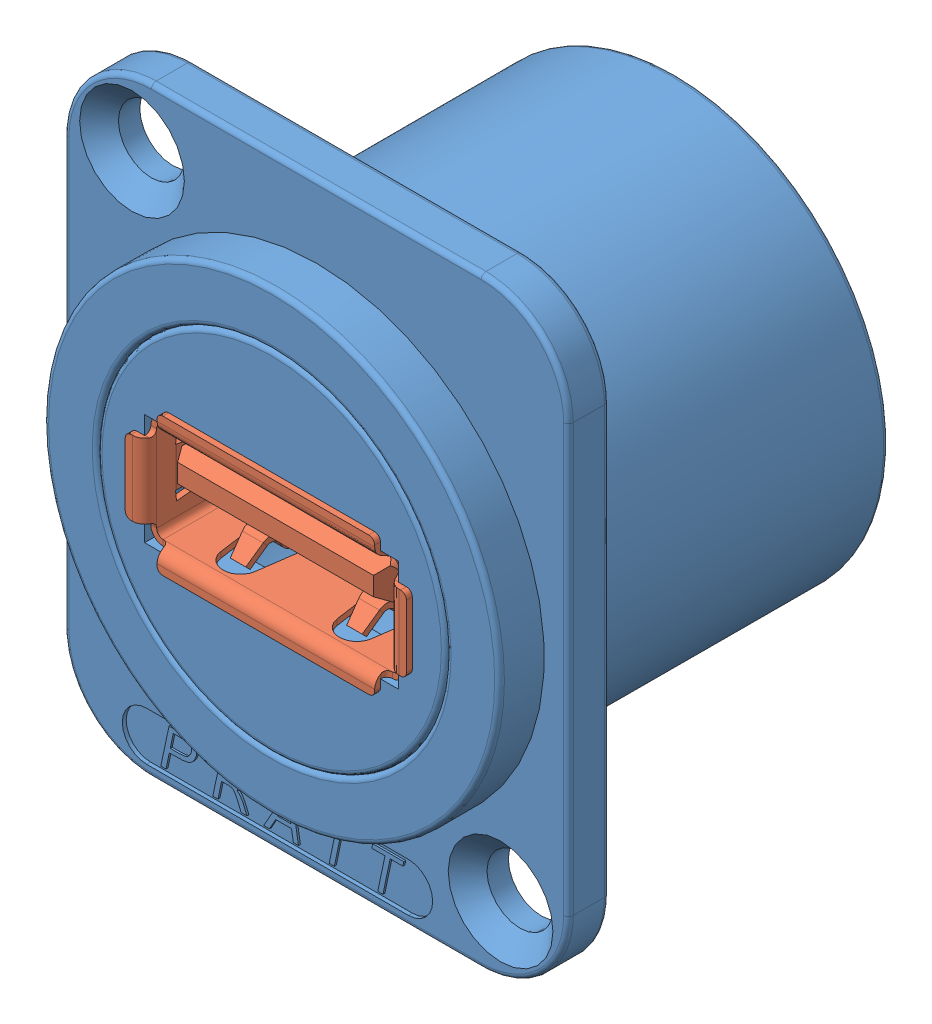
SolidWorks assembly Neutrik USB2-A, configuration Standard. Lengths in mm.
Overall size (26 31 21.1).
2 component instances, 2 part files, 6 mates.
Components (placement in the parent):
- Neutrik-USB2-a-1: Neutrik-USB2-a [Standard] at (-13 -15.5 -2.3) x (1 0 0) z (0 1 0) size (26 20.8 31)
- 96939-1: 96939 [Standard] at (-13 -15.5 0.3) size (15.8 7.12 18.93)
Mates (geometry in assembly coordinates):
- Deckungsgleich1: coincident anti-aligned: plane of Neutrik-USB2-a-1 through (-89.8562 -18.36 -10) normal (0 1 0); plane of 96939-1 through (-102.9562 -18.36 -0.32) normal (0 -1 0)
- Deckungsgleich2: coincident anti-aligned: plane of Neutrik-USB2-a-1 through (-89.8562 -12.64 -10) normal (-1 0 0); plane of 96939-1 through (-89.8562 -15.5 0.3) normal (1 0 0)
- Deckungsgleich3: coincident anti-aligned: plane of Neutrik-USB2-a-1 through (-96.4062 -15.5 0) normal (0 0 1); plane of 96939-1 through (-102.3182 -12.32 0) normal (0 0 -1)
- Deckungsgleich4: coincident aligned: plane of Neutrik-USB2-a-1 through (-13 -15.5 0) normal (0 0 1); plane of assembly
- Deckungsgleich5: coincident aligned: plane of Neutrik-USB2-a-1 through (-4.5 0 -4.4) normal (0 1 0); plane of assembly
- Deckungsgleich6: coincident aligned: plane of Neutrik-USB2-a-1 through (0 -26.5 -4.4) normal (1 0 0); plane of assembly
